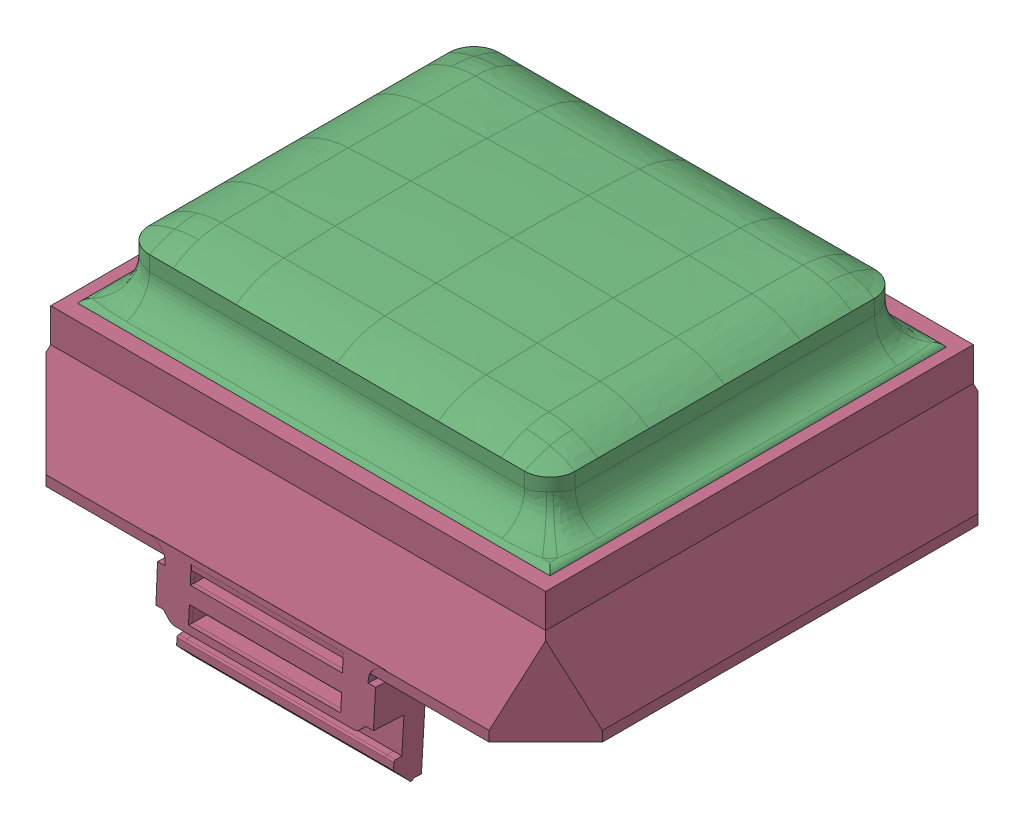
SolidWorks assembly Original, configuration 默认. Lengths in mm.
Overall size (33 18.27 29.5).
4 component instances, 4 part files, 10 mates.
Components (placement in the parent):
- Lens-1: Lens [默认] at origin size (28.33 2.18 23.83)
- InsideSkin-1: InsideSkin [默认] at (0.0001 0 0.2499) size (23.8 5.48 19.29)
- Topskin-1: Topskin [默认] at (0.0001 2 0.2499) size (28.02 6.25 23.52)
- Supportbase-2: Supportbase [默认] at origin size (33 14.02 29.5)
Mates (geometry in assembly coordinates):
- 同心2: concentric anti-aligned: cylinder of NewInsideSkin_conti-1 through (10.8751 17.7531 8.6249) axis (0 1 0) radius 0.7; cylinder of Board3Con1612611OriginalSkin_TOP-1 through (10.8751 24 8.6249) axis (0 -1 0) radius 0.7
- 同心3: concentric anti-aligned: cylinder of NewInsideSkin_conti-1 through (10.8751 17.7531 -9.1251) axis (0 1 0) radius 0.7; cylinder of Board3Con1612611OriginalSkin_TOP-1 through (10.8751 24 -9.1251) axis (0 -1 0) radius 0.7
- 重合4: coincident aligned: plane of NewInsideSkin_conti-1 through (10.8751 19 -9.1251) normal (0 -1 0); plane of Board3Con1612611OriginalSkin_TOP-1 through (0.0001 19 0.2499) normal (0 -1 0)
- 重合6: coordinate: point of NewContiSupportBase-2
- 重合7: coincident anti-aligned: plane of lensall-1 through (13.75 19 -11.5) normal (0.939693 0.34202 0); plane of NewContiSupportBase-2 through (13.75 19 12.7803) normal (-0.939693 -0.34202 0)
- 同心5: concentric aligned: cylinder of lensall-1 through (13.3294 18.6938 -11.0794) axis (-0.323616 0.889126 0.323616) radius 0.5; cylinder of NewContiSupportBase-2 through (10.7866 25.6801 -8.5366) axis (-0.323616 0.889126 0.323616) radius 0.5
- 重合8: coincident anti-aligned: plane of lensall-1 through (0 18 0) normal (0 -1 0); plane of NewContiSupportBase-2 through (0 18 0) normal (0 1 0)
- 重合9: coincident anti-aligned: plane of lensall-1 through (0 19 0) normal (0 1 0); plane of Board3Con1612611OriginalSkin_TOP-1 through (0.0001 19 0.2499) normal (0 -1 0)
- 重合10: coincident anti-aligned: plane of Board3Con1612611OriginalSkin_TOP-1 through (0.0001 19 11.7499) normal (0 0 1); plane of NewContiSupportBase-2 through (-13.5999 21 11.7499) normal (0 0 -1)
- 重合11: coincident anti-aligned: plane of Board3Con1612611OriginalSkin_TOP-1 through (14.0001 19 0.2499) normal (1 0 0); plane of NewContiSupportBase-2 through (14.0001 21 11.7499) normal (-1 0 0)
